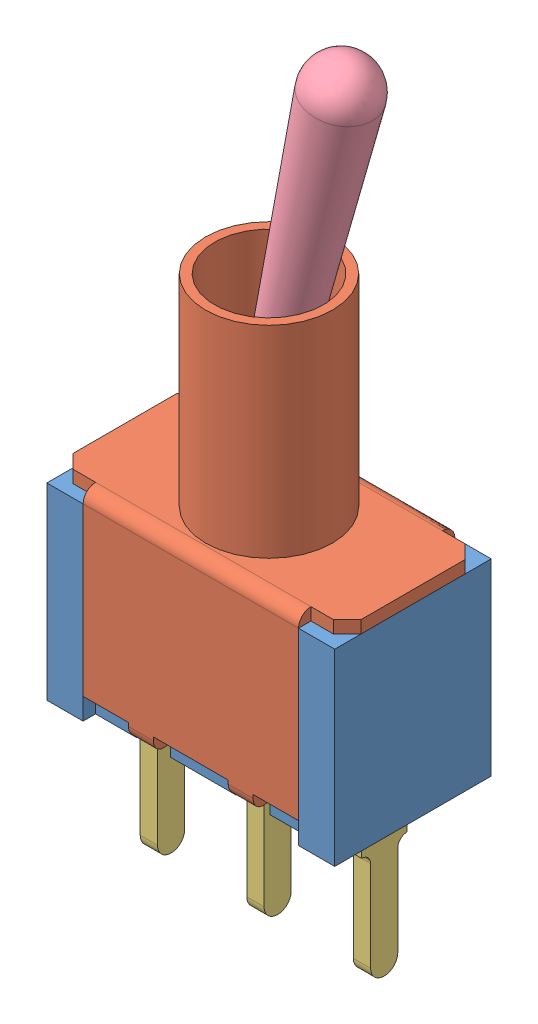
SolidWorks assembly ToggleSwitch_MiniatureToggleSwitch, configuration Default. Lengths in mm.
Overall size (13.21 35.07 6.9).
6 component instances, 4 part files, 13 mates.
Components (placement in the parent):
- Body_MiniatureToggleSwitch-1: Body_MiniatureToggleSwitch [Default] at (-1.0787 4.0041 14.8653) size (12.7 8.35 6.9)
- Shroud_MiniatureToggleSwitch-1: Shroud_MiniatureToggleSwitch [Default] at (11.6213 12.8541 14.3153) x (-1 0 0) z (0 0 1) size (12.7 17.5 6.9)
- Pin_MiniatureToggleSwitch-1: Pin_MiniatureToggleSwitch [Default] at (0.9513 3.9541 12.4153) x (-1 0 0) z (0 0 1) size (0.76 6.5 2)
- Pin_MiniatureToggleSwitch-2: Pin_MiniatureToggleSwitch [Default] at (5.6513 3.9541 12.4153) x (-1 0 0) z (0 0 1) size (0.76 6.5 2)
- Pin_MiniatureToggleSwitch-3: Pin_MiniatureToggleSwitch [Default] at (10.3513 3.9541 12.4153) x (-1 0 0) z (0 0 1) size (0.76 6.5 2)
- Toggle_MiniatureToggleSwitch-1: Toggle_MiniatureToggleSwitch [Default] at (4.7114 14.5203 11.4051) x (0.731974 -0.172739 -0.659072) z (0.64015 -0.156848 0.752068) size (4.8 17.7 4.8)
Mates (geometry in assembly coordinates):
- Coincident1: coincident anti-aligned: plane of Body_MiniatureToggleSwitch-1 through (-1.0787 12.3041 14.8653) normal (0 1 0); plane of Shroud_MiniatureToggleSwitch-1 through (11.6213 12.3041 14.3153) normal (0 -1 0)
- Coincident2: coincident anti-aligned: plane of Body_MiniatureToggleSwitch-1 through (10.0213 12.3041 8.5153) normal (0 0 -1); plane of Shroud_MiniatureToggleSwitch-1 through (11.6213 4.9541 8.5153) normal (0 0 1)
- Coincident3: coincident anti-aligned: plane of Body_MiniatureToggleSwitch-1 through (10.0213 12.3041 14.3153) normal (-1 0 0); plane of Shroud_MiniatureToggleSwitch-1 through (10.0213 4.9541 14.3153) normal (1 0 0)
- Coincident4: coincident anti-aligned: plane of Body_MiniatureToggleSwitch-1 through (-1.0787 3.9541 14.8653) normal (0 -1 0); plane of Pin_MiniatureToggleSwitch-1 through (0.1913 3.9541 12.4153) normal (0 1 0)
- Coincident5: coincident aligned: plane of Body_MiniatureToggleSwitch-1 through (0.9513 3.9541 12.4153) normal (1 0 0); plane of Pin_MiniatureToggleSwitch-1 through (0.9513 3.9541 12.4153) normal (1 0 0)
- Coincident6: coincident aligned: plane of Body_MiniatureToggleSwitch-1 through (0.1913 3.9541 12.4153) normal (0 0 1); plane of Pin_MiniatureToggleSwitch-1 through (0.1913 3.9541 12.4153) normal (0 0 1)
- Coincident7: coincident anti-aligned: plane of Body_MiniatureToggleSwitch-1 through (-1.0787 3.9541 14.8653) normal (0 -1 0); plane of Pin_MiniatureToggleSwitch-2 through (4.8913 3.9541 12.4153) normal (0 1 0)
- Coincident8: coincident aligned: plane of Body_MiniatureToggleSwitch-1 through (5.6513 3.9541 12.4153) normal (1 0 0); plane of Pin_MiniatureToggleSwitch-2 through (5.6513 3.9541 12.4153) normal (1 0 0)
- Coincident9: coincident aligned: plane of Body_MiniatureToggleSwitch-1 through (4.8913 3.9541 12.4153) normal (0 0 1); plane of Pin_MiniatureToggleSwitch-2 through (4.8913 3.9541 12.4153) normal (0 0 1)
- Coincident10: coincident anti-aligned: plane of Body_MiniatureToggleSwitch-1 through (-1.0787 3.9541 14.8653) normal (0 -1 0); plane of Pin_MiniatureToggleSwitch-3 through (9.5913 3.9541 12.4153) normal (0 1 0)
- Coincident11: coincident aligned: plane of Body_MiniatureToggleSwitch-1 through (9.5913 3.9541 12.4153) normal (0 0 1); plane of Pin_MiniatureToggleSwitch-3 through (9.5913 3.9541 12.4153) normal (0 0 1)
- Coincident12: coincident aligned: plane of Body_MiniatureToggleSwitch-1 through (10.3513 3.9541 12.4153) normal (1 0 0); plane of Pin_MiniatureToggleSwitch-3 through (10.3513 3.9541 12.4153) normal (1 0 0)
- Concentric3: concentric: sphere of Shroud_MiniatureToggleSwitch-1; sphere of Toggle_MiniatureToggleSwitch-1
